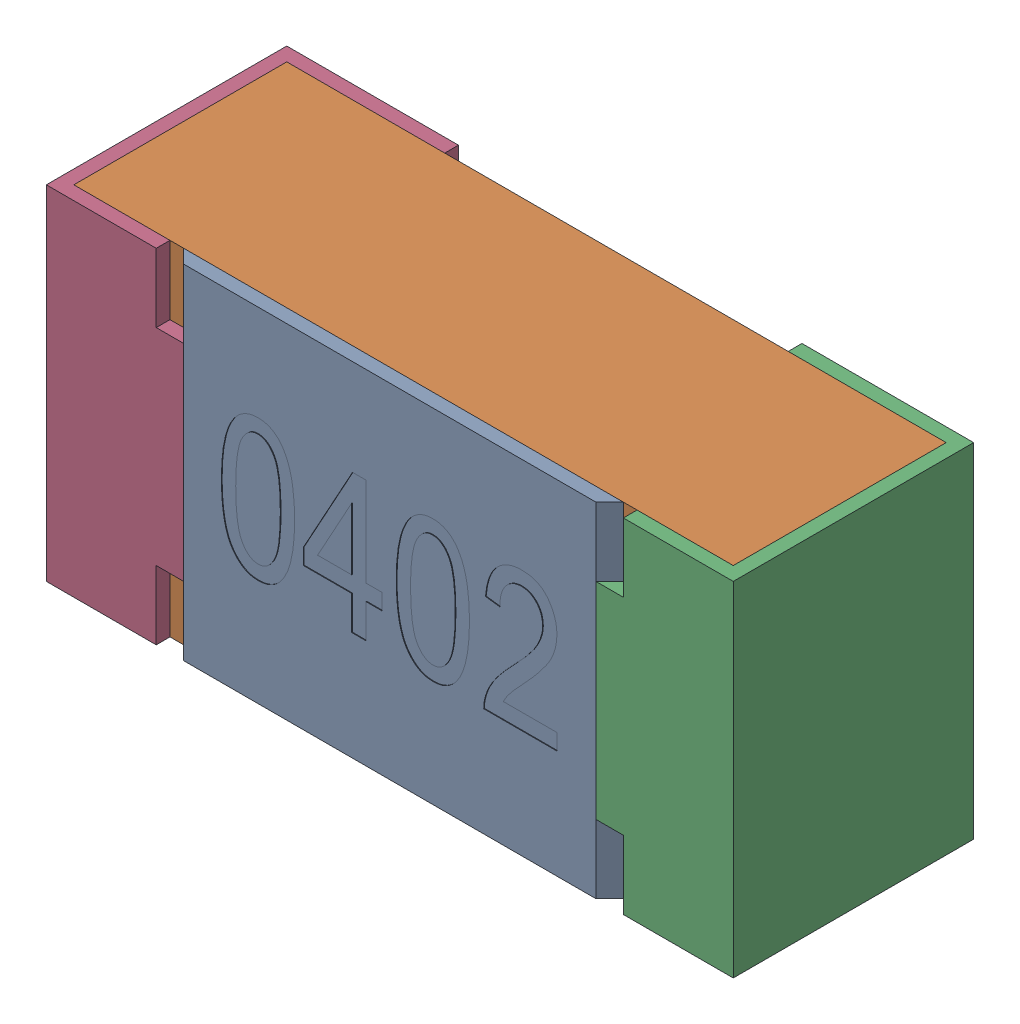
SolidWorks assembly R32, configuration Standard. Lengths in mm.
Overall size (1 0.5 0.35).
5 component instances, 4 part files, 0 mates.
Components (placement in the parent):
- R32-subassembly-1-1: R32-subassembly-1 [Standard] at (8.6001 -10.5 0) x (1 0 0) z (0 0 1) size (1 0.5 0.35)
  - User Library-R_0402-1: User Library-R_0402 [Standard] at origin size (0.64 0.5 0.02)
  - User Library-R_0402-1-1: User Library-R_0402-1 [Standard] at origin size (0.96 0.5 0.31)
  - User Library-R_0402-2-1: User Library-R_0402-2 [Standard] at origin size (0.25 0.5 0.35)
  - User Library-R_0402-3-1: User Library-R_0402-3 [Standard] at origin size (0.25 0.5 0.35)
